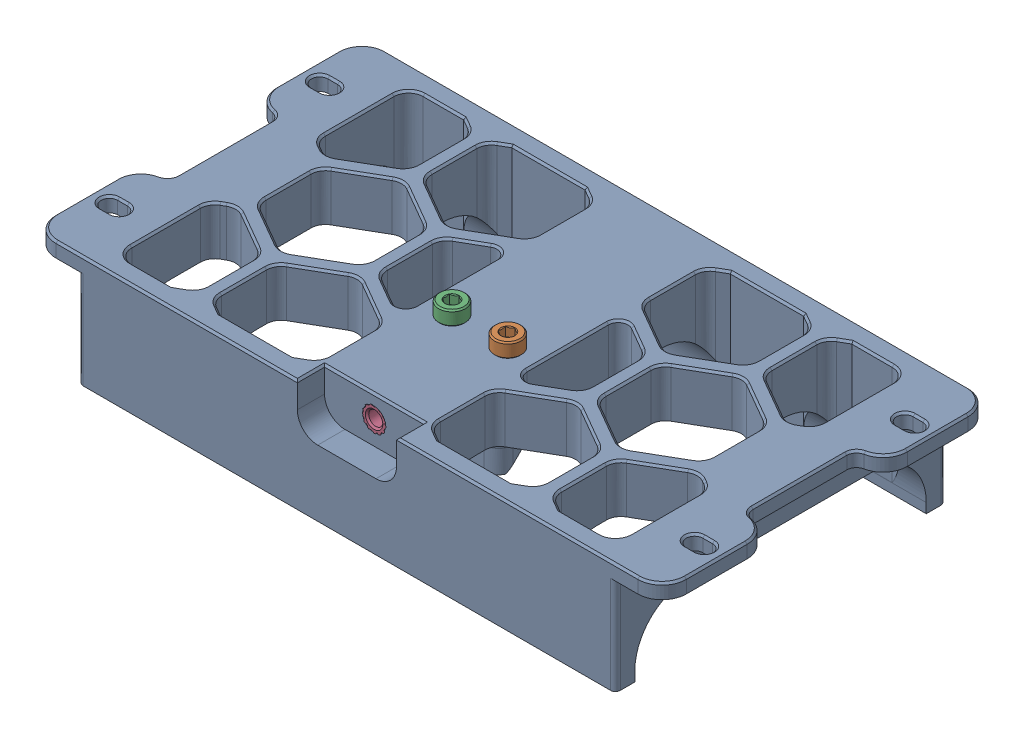
SolidWorks assembly Front Grill Midsection, configuration Default. Lengths in mm.
Overall size (129.81 26.15 68.01).
4 component instances, 3 part files, 0 mates.
Components (placement in the parent):
- Front Grill Midsection-1: Front Grill Midsection [Default] at origin size (129.81 23 68.01)
- M3x12 SHCS (1)-1: M3x12 SHCS (1) [Default] at (5.75 -319 36.602) x (1 0 0) z (0 -1 0) size (5.5 5.5 15.14)
- M3x12 SHCS (1)-2: M3x12 SHCS (1) [Default] at (-5.75 -319 36.602) x (1 0 0) z (0 -1 0) size (5.5 5.5 15.14)
- M3 Threaded Insert (9)-1: M3 Threaded Insert (9) [Default] at (0 -311.6 54.55) size (5 5 3.85)
